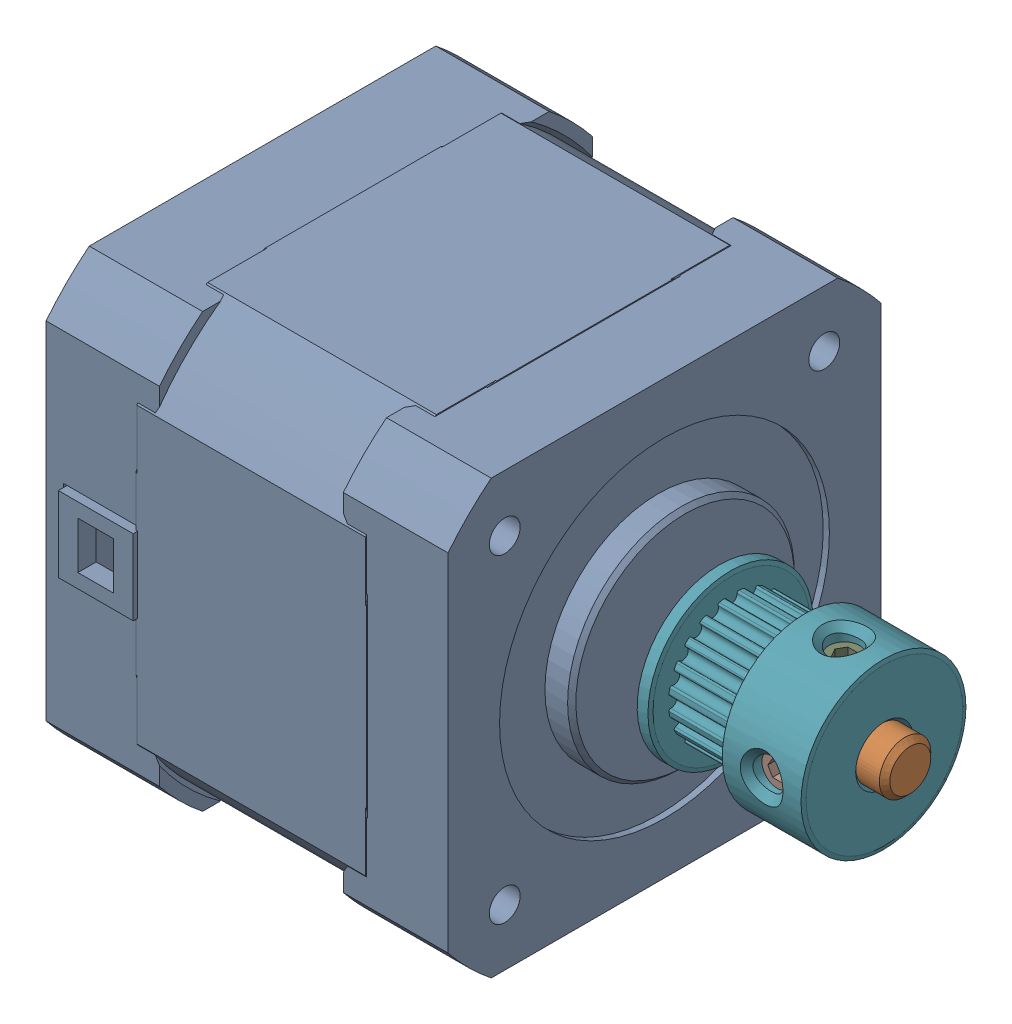
SolidWorks assembly Y Motor, configuration Default. Lengths in mm.
Overall size (62.85 42.2 42.61).
11 component instances, 9 part files, 0 mates.
Components (placement in the parent):
- NEMA17 (Black) v3-1: NEMA17 (Black) v3 [Default] at (-6.36 115.0001 67) x (0 -1 0) z (1 0 0) size (42.2 42.61 62.85)
  - NEMA17 (Black) v3_5-1: NEMA17 (Black) v3_5 [Default] at origin size (42.2 42.61 41)
  - NEMA17 (Black) v3_2-1: NEMA17 (Black) v3_2 [Default] at origin size (5.02 5.02 60.35)
  - NEMA17 (Black) v3_3-1: NEMA17 (Black) v3_3 [Default] at origin size (5.33 5.33 23.75)
  - NEMA17 (Black) v3_4-1: NEMA17 (Black) v3_4 [Default] at origin size (5.33 5.33 23.75)
  - NEMA17 (Black) v3-1: NEMA17 (Black) v3 [Default] at origin size (5.33 5.33 23.75)
  - NEMA17 (Black) v3_6-1: NEMA17 (Black) v3_6 [Default] at origin size (5.33 5.33 23.75)
- GT2 20T 6mm Powge v2-1: GT2 20T 6mm Powge v2 [Default] at (33.55 115.0001 67) x (-1 0 0) z (0 1 0) size (16 16 16)
  - GT2 20T 6mm Powge v2_2-1: GT2 20T 6mm Powge v2_2 [Default] at origin size (16 16 16)
  - GT2 20T 6mm Powge v2-1: GT2 20T 6mm Powge v2 [Default] at origin size (3 4 3)
  - GT2 20T 6mm Powge v2_3-1: GT2 20T 6mm Powge v2_3 [Default] at origin size (3 3 4)
